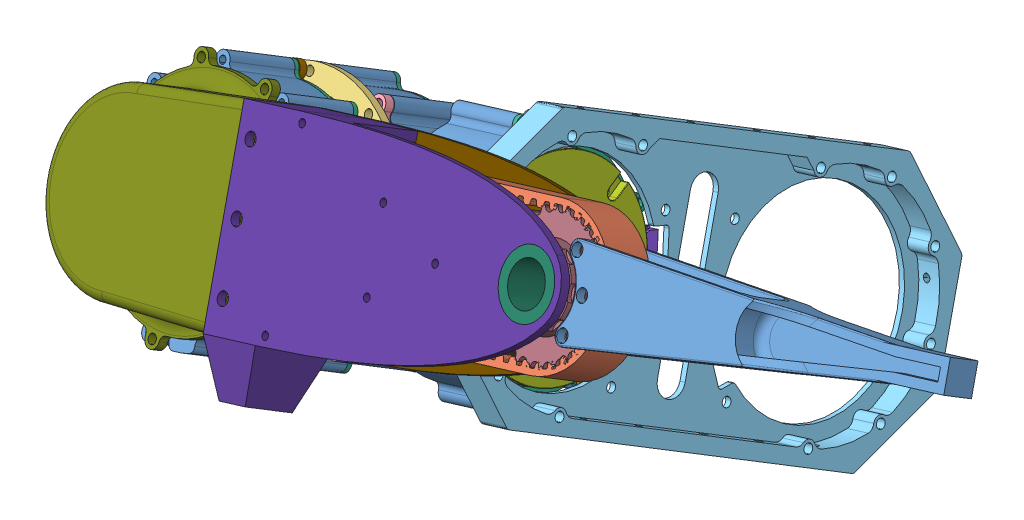
SolidWorks assembly 测试机械腿装配体, configuration 默认. Lengths in mm.
Overall size (357.51 213.54 232.86).
75 component instances, 23 part files, 47 mates.
Components (placement in the parent):
- CyberGearmotor.stp-1: CyberGearmotor.stp [默认] at (-16.9975 318.524 149.0781) x (0.513377 -0.714646 0.475105) z (0.144334 -0.473839 -0.868703) size (96.28 96.17 36.5)
  - ASM0002_ASM_1_ASM.stp-1: ASM0002_ASM_1_ASM.stp [默认] at origin size (96.28 96.17 36.5)
    - ASM0002_ASM_1_ASM_1_ASM.stp-1: ASM0002_ASM_1_ASM_1_ASM.stp [默认] at origin size (96.28 96.17 36.5)
      - 0714_ASM_1_ASM_1_ASM_1_ASM.stp-1: 0714_ASM_1_ASM_1_ASM_1_ASM.stp [默认] at origin size (96.28 96.17 36.5)
        - 3_1_02_067_0003_ASM_ASM_1_ASM_1_ASM.stp-1: 3_1_02_067_0003_ASM_ASM_1_ASM_1_ASM.stp [默认] at origin size (96.28 96.17 36.5)
          - 3_1_02_067_0003_ASM_1_ASM_1_ASM_ASM.stp-1: 3_1_02_067_0003_ASM_1_ASM_1_ASM_ASM.stp [默认] at origin size (96.28 96.17 36.5)
            - 1_1_06_EB673-504_1_1_1_1_1.stp-1: 1_1_06_EB673-504_1_1_1_1_1.stp [默认] at (39.8324 39.833 -22) size (79.19 78.95 25.5)
            - 1_2_04_670601_1_1_1_1_1.stp-1: 1_2_04_670601_1_1_1_1_1.stp [默认] at (93.9161 79.9966 -44) size (37 37 4)
            - 1_1_02_EB671-500_1_1_1_1_1.stp-1: 1_1_02_EB671-500_1_1_1_1_1.stp [默认] at (93.9161 79.9966 -44.4) x (-0.960973 0.276644 0) z (0 0 1) size (33 33 8.5)
            - 1_2_04_694000_1_1_1_1_1.stp-1: 1_2_04_694000_1_1_1_1_1.stp [默认] at (93.9161 79.9966 -44.5) size (11 11 4)
            - 1_2_06_000213_1_1_1_1_1.stp-1: 1_2_06_000213_1_1_1_1_1.stp [默认] at (93.9161 79.9966 -45.5) size (38.8 36.2 1.5)
            - 1_1_31_QT-642_1_1_1_1_1.stp-1: 1_1_31_QT-642_1_1_1_1_1.stp [默认] at (93.9161 79.9966 -22) x (-0.970555 -0.24088 0) z (0 0 -1) size (79.5 79.36 6)
            - 1_1_06_EB673-502_1_1_1_1_1.stp-1: 1_1_06_EB673-502_1_1_1_1_1.stp [默认] at (93.9161 79.9966 -13) x (-0.515958 -0.856614 0) z (0 0 -1) size (63 63 8)
          - 0518_ASM_2_ASM_1_ASM_1_ASM_1_AS_ASM.stp-1: 0518_ASM_2_ASM_1_ASM_1_ASM_1_AS_ASM.stp [默认] at (93.9161 79.9966 -17.235) x (0.235897 -0.971778 0) z (0 0 1) size (15.5 11.3 5.2)
            - 12345_ASM_1_ASM_2_ASM_1_ASM_1_A_ASM.stp-1: 12345_ASM_1_ASM_2_ASM_1_ASM_1_A_ASM.stp [默认] at origin size (15.5 11.3 5.2)
              - DUANZI_1_3_1_1_1_1_1_1.stp-1: DUANZI_1_3_1_1_1_1_1_1.stp [默认] at (-0.1798 16.5474 0.4329) x (0 0 -1) z (0 1 0) size (5.2 15.5 11.3)
      - LUODING_1_1.stp-1: LUODING_1_1.stp [默认] at (119.9375 52.9941 -20.5) x (-1 0 0) z (0 1 0) size (5.68 3 5.68)
      - LUODING_1_1.stp-2: LUODING_1_1.stp [默认] at (104.2902 116.0331 -20.5) x (-1 0 0) z (0 1 0) size (5.68 3 5.68)
      - LUODING_1_1.stp-3: LUODING_1_1.stp [默认] at (57.5205 70.9626 -20.5) x (-1 0 0) z (0 1 0) size (5.68 3 5.68)
  - 0411-2_4_1_3_1.stp-1: 0411-2_4_1_3_1.stp [默认] at (93.9161 79.9964 -17.5) x (0.235904 -0.971776 0) z (0 0 1) size (58 56.68 1.62)
- 带轮-1: 带轮 [默认] at (-46.1979 242.2295 263.5439) x (-0.758521 0.510794 -0.404643) z (0.144334 -0.473839 -0.868703) size (43.22 43.22 15)
- 带轮挡边-1: 带轮挡边 [默认] at (-44.0329 235.1219 250.5133) x (-0.758521 0.510794 -0.404643) z (0.144334 -0.473839 -0.868703) size (50 50 4)
- 带轮挡边-2: 带轮挡边 [默认] at (-46.7752 244.1248 267.0187) x (-0.171067 -0.876625 0.449738) z (0.144334 -0.473839 -0.868703) size (50 50 4)
- 膝关节带轮-1: 膝关节带轮 [默认] at (97.8102 306.0925 252.6362) x (-0.253129 0.831006 -0.495334) z (0.144334 -0.473839 -0.868703) size (43.22 43.22 23)
- 轴承-1: 轴承 [默认] at (105.7027 278.9198 247.4729) x (-0.639215 -0.714793 0.283683) z (-0.144334 0.473839 0.868703) size (23 23 4)
- 轴承-2: 轴承 [默认] at (102.9604 287.9227 263.9782) x (0.978394 -0.062991 0.196918) z (-0.144334 0.473839 0.868703) size (23 23 4)
- 膝关节转轴-1: 膝关节转轴 [默认] at (106.0635 277.7352 245.3011) x (-0.660093 -0.700126 0.272215) z (-0.144334 0.473839 0.868703) size (21 21 29)
- 大腿根部SLDPRT-3: 大腿根部SLDPRT [默认] at (-116.5184 238.2995 228.6787) x (-0.867463 -0.482981 0.119317) z (-0.144334 0.473839 0.868703) size (94.61 80.14 30.19)
- 大腿前部-1: 大腿前部 [默认] at (28.4879 261.8799 274.4435) x (0.253129 -0.831006 0.495334) z (0.956605 0.291387 0) size (78.5 27.01 129)
- 大腿前部盖子-1: 大腿前部盖子 [默认] at (28.7808 260.9183 240.4824) x (-0.253129 0.831006 -0.495334) z (0.956605 0.291387 0) size (72.83 15.76 129)
- 小腿2-1: 小腿2 [默认] at (167.4944 300.8487 252.6851) x (0.956605 0.291387 0) z (0.253129 -0.831006 0.495334) size (141.69 21.45 28.63)
- 5m同步带1-1: 5m同步带1 [默认] at (103.168 283.8435 257.0286) x (-0.144334 0.473839 0.868703) z (0.956605 0.291387 0) size (15 46.9 201.91)
- 连接盘-1: 连接盘 [默认] at (-38.0537 214.0176 210.6413) x (-0.962688 -0.270324 -0.0125) z (-0.228908 0.838094 -0.495176) size (80.5 7 80.5)
- CyberGearmotor.stp-2: CyberGearmotor.stp [默认] at (50.6838 277.1601 135.113) x (-0.021389 -0.879184 0.476002) z (0.144334 -0.473839 -0.868703) size (96.28 96.17 36.5)
  - ASM0002_ASM_1_ASM.stp-1: ASM0002_ASM_1_ASM.stp [默认] at origin size (96.28 96.17 36.5)
    - ASM0002_ASM_1_ASM_1_ASM.stp-1: ASM0002_ASM_1_ASM_1_ASM.stp [默认] at origin size (96.28 96.17 36.5)
      - 0714_ASM_1_ASM_1_ASM_1_ASM.stp-1: 0714_ASM_1_ASM_1_ASM_1_ASM.stp [默认] at origin size (96.28 96.17 36.5)
        - 3_1_02_067_0003_ASM_ASM_1_ASM_1_ASM.stp-1: 3_1_02_067_0003_ASM_ASM_1_ASM_1_ASM.stp [默认] at origin size (96.28 96.17 36.5)
          - 3_1_02_067_0003_ASM_1_ASM_1_ASM_ASM.stp-1: 3_1_02_067_0003_ASM_1_ASM_1_ASM_ASM.stp [默认] at origin size (96.28 96.17 36.5)
            - 1_1_06_EB673-504_1_1_1_1_1.stp-1: 1_1_06_EB673-504_1_1_1_1_1.stp [默认] at (39.8324 39.833 -22) size (79.19 78.95 25.5)
            - 1_2_04_670601_1_1_1_1_1.stp-1: 1_2_04_670601_1_1_1_1_1.stp [默认] at (93.9161 79.9966 -44) size (37 37 4)
            - 1_1_02_EB671-500_1_1_1_1_1.stp-1: 1_1_02_EB671-500_1_1_1_1_1.stp [默认] at (93.9161 79.9966 -44.4) x (-0.960973 0.276644 0) z (0 0 1) size (33 33 8.5)
            - 1_2_04_694000_1_1_1_1_1.stp-1: 1_2_04_694000_1_1_1_1_1.stp [默认] at (93.9161 79.9966 -44.5) size (11 11 4)
            - 1_2_06_000213_1_1_1_1_1.stp-1: 1_2_06_000213_1_1_1_1_1.stp [默认] at (93.9161 79.9966 -45.5) size (38.8 36.2 1.5)
            - 1_1_31_QT-642_1_1_1_1_1.stp-1: 1_1_31_QT-642_1_1_1_1_1.stp [默认] at (93.9161 79.9966 -22) x (-0.970555 -0.24088 0) z (0 0 -1) size (79.5 79.36 6)
            - 1_1_06_EB673-502_1_1_1_1_1.stp-1: 1_1_06_EB673-502_1_1_1_1_1.stp [默认] at (93.9161 79.9966 -13) x (-0.515958 -0.856614 0) z (0 0 -1) size (63 63 8)
          - 0518_ASM_2_ASM_1_ASM_1_ASM_1_AS_ASM.stp-1: 0518_ASM_2_ASM_1_ASM_1_ASM_1_AS_ASM.stp [默认] at (93.9161 79.9966 -17.235) x (0.235897 -0.971778 0) z (0 0 1) size (15.5 11.3 5.2)
            - 12345_ASM_1_ASM_2_ASM_1_ASM_1_A_ASM.stp-1: 12345_ASM_1_ASM_2_ASM_1_ASM_1_A_ASM.stp [默认] at origin size (15.5 11.3 5.2)
              - DUANZI_1_3_1_1_1_1_1_1.stp-1: DUANZI_1_3_1_1_1_1_1_1.stp [默认] at (-0.1798 16.5474 0.4329) x (0 0 -1) z (0 1 0) size (5.2 15.5 11.3)
      - LUODING_1_1.stp-1: LUODING_1_1.stp [默认] at (119.9375 52.9941 -20.5) x (-1 0 0) z (0 1 0) size (5.68 3 5.68)
      - LUODING_1_1.stp-2: LUODING_1_1.stp [默认] at (104.2902 116.0331 -20.5) x (-1 0 0) z (0 1 0) size (5.68 3 5.68)
      - LUODING_1_1.stp-3: LUODING_1_1.stp [默认] at (57.5205 70.9626 -20.5) x (-1 0 0) z (0 1 0) size (5.68 3 5.68)
  - 0411-2_4_1_3_1.stp-1: 0411-2_4_1_3_1.stp [默认] at (93.9161 79.9964 -17.5) x (0.235904 -0.971776 0) z (0 0 1) size (58 56.68 1.62)
- 肩关节连接器-1: 肩关节连接器 [默认] at (-5.8984 160.7238 245.2835) x (-0.021415 -0.879185 0.475999) z (0.989297 0.050099 0.137044) size (67.92 38.09 40.7)
- CyberGearmotor.stp-3: CyberGearmotor.stp [默认] at (56.3683 218.9179 320.1116) x (0.161386 -0.529819 -0.832614) z (0.956605 0.291387 0) size (96.28 96.17 36.5)
  - ASM0002_ASM_1_ASM.stp-1: ASM0002_ASM_1_ASM.stp [默认] at origin size (96.28 96.17 36.5)
    - ASM0002_ASM_1_ASM_1_ASM.stp-1: ASM0002_ASM_1_ASM_1_ASM.stp [默认] at origin size (96.28 96.17 36.5)
      - 0714_ASM_1_ASM_1_ASM_1_ASM.stp-1: 0714_ASM_1_ASM_1_ASM_1_ASM.stp [默认] at origin size (96.28 96.17 36.5)
        - 3_1_02_067_0003_ASM_ASM_1_ASM_1_ASM.stp-1: 3_1_02_067_0003_ASM_ASM_1_ASM_1_ASM.stp [默认] at origin size (96.28 96.17 36.5)
          - 3_1_02_067_0003_ASM_1_ASM_1_ASM_ASM.stp-1: 3_1_02_067_0003_ASM_1_ASM_1_ASM_ASM.stp [默认] at origin size (96.28 96.17 36.5)
            - 1_1_06_EB673-504_1_1_1_1_1.stp-1: 1_1_06_EB673-504_1_1_1_1_1.stp [默认] at (39.8324 39.833 -22) size (79.19 78.95 25.5)
            - 1_2_04_670601_1_1_1_1_1.stp-1: 1_2_04_670601_1_1_1_1_1.stp [默认] at (93.9161 79.9966 -44) size (37 37 4)
            - 1_1_02_EB671-500_1_1_1_1_1.stp-1: 1_1_02_EB671-500_1_1_1_1_1.stp [默认] at (93.9161 79.9966 -44.4) x (-0.960973 0.276644 0) z (0 0 1) size (33 33 8.5)
            - 1_2_04_694000_1_1_1_1_1.stp-1: 1_2_04_694000_1_1_1_1_1.stp [默认] at (93.9161 79.9966 -44.5) size (11 11 4)
            - 1_2_06_000213_1_1_1_1_1.stp-1: 1_2_06_000213_1_1_1_1_1.stp [默认] at (93.9161 79.9966 -45.5) size (38.8 36.2 1.5)
            - 1_1_31_QT-642_1_1_1_1_1.stp-1: 1_1_31_QT-642_1_1_1_1_1.stp [默认] at (93.9161 79.9966 -22) x (-0.970555 -0.24088 0) z (0 0 -1) size (79.5 79.36 6)
            - 1_1_06_EB673-502_1_1_1_1_1.stp-1: 1_1_06_EB673-502_1_1_1_1_1.stp [默认] at (93.9161 79.9966 -13) x (-0.515958 -0.856614 0) z (0 0 -1) size (63 63 8)
          - 0518_ASM_2_ASM_1_ASM_1_ASM_1_AS_ASM.stp-1: 0518_ASM_2_ASM_1_ASM_1_ASM_1_AS_ASM.stp [默认] at (93.9161 79.9966 -17.235) x (0.235897 -0.971778 0) z (0 0 1) size (15.5 11.3 5.2)
            - 12345_ASM_1_ASM_2_ASM_1_ASM_1_A_ASM.stp-1: 12345_ASM_1_ASM_2_ASM_1_ASM_1_A_ASM.stp [默认] at origin size (15.5 11.3 5.2)
              - DUANZI_1_3_1_1_1_1_1_1.stp-1: DUANZI_1_3_1_1_1_1_1_1.stp [默认] at (-0.1798 16.5474 0.4329) x (0 0 -1) z (0 1 0) size (5.2 15.5 11.3)
      - LUODING_1_1.stp-1: LUODING_1_1.stp [默认] at (119.9375 52.9941 -20.5) x (-1 0 0) z (0 1 0) size (5.68 3 5.68)
      - LUODING_1_1.stp-2: LUODING_1_1.stp [默认] at (104.2902 116.0331 -20.5) x (-1 0 0) z (0 1 0) size (5.68 3 5.68)
      - LUODING_1_1.stp-3: LUODING_1_1.stp [默认] at (57.5205 70.9626 -20.5) x (-1 0 0) z (0 1 0) size (5.68 3 5.68)
  - 0411-2_4_1_3_1.stp-1: 0411-2_4_1_3_1.stp [默认] at (93.9161 79.9964 -17.5) x (0.235904 -0.971776 0) z (0 0 1) size (58 56.68 1.62)
- 肩膀-1: 肩膀 [默认] at (40.6375 229.3786 197.6094) x (0.144334 -0.473839 -0.868703) z (0.253129 -0.831006 0.495334) size (175 10 85)
Mates (geometry in assembly coordinates):
- 同心1: concentric aligned: cylinder of CyberGearmotor.stp-1/ASM0002_ASM_1_ASM.stp-1/ASM0002_ASM_1_ASM_1_ASM.stp-1/0714_ASM_1_ASM_1_ASM_1_ASM.stp-1/3_1_02_067_0003_ASM_ASM_1_ASM_1_ASM.stp-1/3_1_02_067_0003_ASM_1_ASM_1_ASM_ASM.stp-1/1_1_02_EB671-500_1_1_1_1_1.stp-1 through (-42.8638 231.2838 243.4769) axis (-0.144334 0.473839 0.868703) radius 16.5; cylinder of 带轮挡边-1 through (-43.4556 233.2265 247.0385) axis (-0.144334 0.473839 0.868703) radius 25
- 重合1: coincident anti-aligned: plane of CyberGearmotor.stp-1/ASM0002_ASM_1_ASM.stp-1/ASM0002_ASM_1_ASM_1_ASM.stp-1/0714_ASM_1_ASM_1_ASM_1_ASM.stp-1/3_1_02_067_0003_ASM_ASM_1_ASM_1_ASM.stp-1/3_1_02_067_0003_ASM_1_ASM_1_ASM_ASM.stp-1/1_1_02_EB671-500_1_1_1_1_1.stp-1 through (-43.4556 233.2265 247.0385) normal (-0.144334 0.473839 0.868703); plane of 带轮挡边-1 through (-43.4556 233.2265 247.0385) normal (0.144334 -0.473839 -0.868703)
- 重合4: coincident anti-aligned: plane of 带轮-1 through (-32.6774 251.5874 243.4188) normal (0.144334 -0.473839 -0.868703); plane of 带轮挡边-1 through (-44.0329 235.1219 250.5133) normal (-0.144334 0.473839 0.868703)
- 同心12: concentric aligned: cylinder of CyberGearmotor.stp-1/ASM0002_ASM_1_ASM.stp-1/ASM0002_ASM_1_ASM_1_ASM.stp-1/0714_ASM_1_ASM_1_ASM_1_ASM.stp-1/3_1_02_067_0003_ASM_ASM_1_ASM_1_ASM.stp-1/3_1_02_067_0003_ASM_1_ASM_1_ASM_ASM.stp-1/1_1_02_EB671-500_1_1_1_1_1.stp-1 through (-42.8638 231.2838 243.4769) axis (-0.144334 0.473839 0.868703) radius 16.5; cylinder of 带轮挡边-2 through (-46.1979 242.2295 263.5439) axis (-0.144334 0.473839 0.868703) radius 25
- 重合5: coincident anti-aligned: plane of 带轮-1 through (-34.8425 258.695 256.4493) normal (-0.144334 0.473839 0.868703); plane of 带轮挡边-2 through (-46.1979 242.2295 263.5439) normal (0.144334 -0.473839 -0.868703)
- 同心20: concentric aligned: cylinder of 轴承-1 through (105.1254 280.8151 250.9477) axis (0.144334 -0.473839 -0.868703) radius 8.5; cylinder of 膝关节转轴-1 through (102.0222 291.0027 269.6248) axis (0.144334 -0.473839 -0.868703) radius 8.5
- 重合12: coincident anti-aligned: plane of CyberGearmotor.stp-1/ASM0002_ASM_1_ASM.stp-1/ASM0002_ASM_1_ASM_1_ASM.stp-1/0714_ASM_1_ASM_1_ASM_1_ASM.stp-1/3_1_02_067_0003_ASM_ASM_1_ASM_1_ASM.stp-1/3_1_02_067_0003_ASM_1_ASM_1_ASM_ASM.stp-1/1_1_06_EB673-504_1_1_1_1_1.stp-1 through (-42.2096 231.838 244.5495) normal (-0.144334 0.473839 0.868703); plane of 大腿根部SLDPRT-3 through (-116.5184 238.2995 228.6787) normal (0.144334 -0.473839 -0.868703)
- 重合17: coincident anti-aligned: plane of 大腿根部SLDPRT-3 through (-7.1399 285.5975 252.1337) normal (-0.144334 0.473839 0.868703); plane of 大腿前部-1 through (28.9209 260.4584 271.8374) normal (0.144334 -0.473839 -0.868703)
- 重合18: coincident anti-aligned: plane of 大腿根部SLDPRT-3 through (-12.8089 269.8899 228.6787) normal (0.956605 0.291387 0); plane of 大腿前部-1 through (-6.6368 249.6273 271.8374) normal (-0.956605 -0.291387 0)
- 重合21: coincident anti-aligned: plane of 大腿根部SLDPRT-3 through (11.8953 223.1062 258.3018) normal (0.253129 -0.831006 0.495334); plane of 大腿前部-1 through (37.454 232.4449 260.9079) normal (-0.253129 0.831006 -0.495334)
- 同心32: concentric anti-aligned: cylinder of 膝关节转轴-1 through (102.0222 291.0027 269.6248) axis (0.144334 -0.473839 -0.868703) radius 8.5; cylinder of 大腿前部-1 through (102.3109 290.055 267.8874) axis (-0.144334 0.473839 0.868703) radius 8.5
- 重合23: coincident aligned: plane of 膝关节转轴-1 through (101.8779 291.4765 270.4935) normal (-0.144334 0.473839 0.868703); plane of 大腿前部-1 through (28.4879 261.8799 274.4435) normal (-0.144334 0.473839 0.868703)
- 重合32: coincident anti-aligned: plane of 带轮挡边-1 through (-44.0329 235.1219 250.5133) normal (-0.144334 0.473839 0.868703); plane of 5m同步带1-1 through (99.277 296.6173 240.781) normal (0.144334 -0.473839 -0.868703)
- 同心44: concentric aligned: cylinder of 带轮挡边-1 through (-43.4556 233.2265 247.0385) axis (-0.144334 0.473839 0.868703) radius 25; cylinder of 5m同步带1-1 through (-45.1154 238.6757 257.0286) axis (-0.144334 0.473839 0.868703) radius 23.448
- 同心47: concentric anti-aligned: cylinder of 膝关节带轮-1 through (105.1975 280.5782 250.5133) axis (-0.144334 0.473839 0.868703) radius 10.5; cylinder of 膝关节转轴-1 through (102.0222 291.0027 269.6248) axis (0.144334 -0.473839 -0.868703) radius 8.5
- 重合38: coincident anti-aligned: plane of 带轮-1 through (-32.6774 251.5874 243.4188) normal (0.144334 -0.473839 -0.868703); plane of 带轮挡边-1 through (-44.0329 235.1219 250.5133) normal (-0.144334 0.473839 0.868703)
- 重合39: coincident aligned: plane of 带轮-1 through (-34.8425 258.695 256.4493) normal (-0.144334 0.473839 0.868703); plane of 膝关节带轮-1 through (122.457 296.0468 262.2107) normal (-0.144334 0.473839 0.868703)
- 重合41: coincident anti-aligned: plane of 膝关节带轮-1 through (105.1819 280.829 250.9495) normal (0.144334 -0.473839 -0.868703); plane of 轴承-1 through (105.1254 280.8151 250.9477) normal (-0.144334 0.473839 0.868703)
- 重合42: coincident anti-aligned: plane of 膝关节带轮-1 through (122.457 296.0468 262.2107) normal (-0.144334 0.473839 0.868703); plane of 小腿2-1 through (165.6902 306.7716 263.5439) normal (0.144334 -0.473839 -0.868703)
- 同心50: concentric aligned: cylinder of 膝关节带轮-1 through (118.8841 274.4731 256.1174) axis (0.144334 -0.473839 -0.868703) radius 1.65; cylinder of 小腿2-1 through (112.1004 296.7436 296.9464) axis (0.144334 -0.473839 -0.868703) radius 2.1
- 同心51: concentric aligned: cylinder of 膝关节带轮-1 through (120.5032 285.2404 250.5133) axis (0.144334 -0.473839 -0.868703) radius 1.65; cylinder of 小腿2-1 through (113.7195 307.5108 291.3424) axis (0.144334 -0.473839 -0.868703) radius 2.1
- 同心53: concentric aligned: circle of 轴承-2; cylinder of 膝关节转轴-1 through (105.3419 280.1044 249.6446) axis (-0.144334 0.473839 0.868703) radius 7
- 重合44: coincident anti-aligned: plane of 大腿根部SLDPRT-3 through (-3.6758 274.2253 231.2848) normal (0.144334 -0.473839 -0.868703); plane of 大腿前部盖子-1 through (28.3478 262.3398 243.0885) normal (-0.144334 0.473839 0.868703)
- 同心54: concentric anti-aligned: cylinder of 大腿根部SLDPRT-3 through (-9.188 275.1622 257.4854) axis (-0.144334 0.473839 0.868703) radius 1.65; cylinder of 大腿前部盖子-1 through (-5.724 263.79 236.6365) axis (0.144334 -0.473839 -0.868703) radius 2.1
- 同心55: concentric anti-aligned: cylinder of 大腿根部SLDPRT-3 through (1.4434 240.2599 278.2894) axis (-0.144334 0.473839 0.868703) radius 1.65; cylinder of 大腿前部盖子-1 through (4.9074 228.8878 257.4405) axis (0.144334 -0.473839 -0.868703) radius 2.1
- 重合45: coincident anti-aligned: plane of CyberGearmotor.stp-1/ASM0002_ASM_1_ASM.stp-1/ASM0002_ASM_1_ASM_1_ASM.stp-1/0714_ASM_1_ASM_1_ASM_1_ASM.stp-1/3_1_02_067_0003_ASM_ASM_1_ASM_1_ASM.stp-1/3_1_02_067_0003_ASM_1_ASM_1_ASM_ASM.stp-1/1_1_06_EB673-502_1_1_1_1_1.stp-1 through (-38.1874 215.9314 215.3309) normal (0.144334 -0.473839 -0.868703); plane of 连接盘-1 through (-38.7753 216.3868 214.9848) normal (-0.144334 0.473839 0.868703)
- 同心56: concentric aligned: cylinder of CyberGearmotor.stp-1/ASM0002_ASM_1_ASM.stp-1/ASM0002_ASM_1_ASM_1_ASM.stp-1/0714_ASM_1_ASM_1_ASM_1_ASM.stp-1/3_1_02_067_0003_ASM_ASM_1_ASM_1_ASM.stp-1/3_1_02_067_0003_ASM_1_ASM_1_ASM_ASM.stp-1/1_1_06_EB673-502_1_1_1_1_1.stp-1 through (-39.342 219.7221 222.2805) axis (0.144334 -0.473839 -0.868703) radius 31.5; cylinder of 连接盘-1 through (-38.1874 215.9314 215.3309) axis (0.144334 -0.473839 -0.868703) radius 40.25
- 同心57: concentric aligned: cylinder of CyberGearmotor.stp-1/ASM0002_ASM_1_ASM.stp-1/ASM0002_ASM_1_ASM_1_ASM.stp-1/0714_ASM_1_ASM_1_ASM_1_ASM.stp-1/3_1_02_067_0003_ASM_ASM_1_ASM_1_ASM.stp-1/3_1_02_067_0003_ASM_1_ASM_1_ASM_ASM.stp-1/1_1_31_QT-642_1_1_1_1_1.stp-1 through (-25.1026 251.3327 207.9798) axis (0.144334 -0.473839 -0.868703) radius 1.55; cylinder of 连接盘-1 through (-23.8757 247.305 200.5958) axis (0.144334 -0.473839 -0.868703) radius 1.55
- 同心61: concentric aligned: cylinder of CyberGearmotor.stp-1/ASM0002_ASM_1_ASM.stp-1/ASM0002_ASM_1_ASM_1_ASM.stp-1/0714_ASM_1_ASM_1_ASM_1_ASM.stp-1/3_1_02_067_0003_ASM_ASM_1_ASM_1_ASM.stp-1/3_1_02_067_0003_ASM_1_ASM_1_ASM_ASM.stp-1/1_1_06_EB673-502_1_1_1_1_1.stp-1 through (-39.342 219.7221 222.2805) axis (0.144334 -0.473839 -0.868703) radius 31.5; cylinder of CyberGearmotor.stp-2/ASM0002_ASM_1_ASM.stp-1/ASM0002_ASM_1_ASM_1_ASM.stp-1/0714_ASM_1_ASM_1_ASM_1_ASM.stp-1/3_1_02_067_0003_ASM_ASM_1_ASM_1_ASM.stp-1/3_1_02_067_0003_ASM_1_ASM_1_ASM_ASM.stp-1/1_1_06_EB673-502_1_1_1_1_1.stp-1 through (-33.3522 200.0578 186.2293) axis (0.144334 -0.473839 -0.868703) radius 31.5
- 重合48: coincident anti-aligned: plane of 连接盘-1 through (-38.0537 214.0176 210.6413) normal (0.144334 -0.473839 -0.868703); plane of CyberGearmotor.stp-2/ASM0002_ASM_1_ASM.stp-1/ASM0002_ASM_1_ASM_1_ASM.stp-1/0714_ASM_1_ASM_1_ASM_1_ASM.stp-1/3_1_02_067_0003_ASM_ASM_1_ASM_1_ASM.stp-1/3_1_02_067_0003_ASM_1_ASM_1_ASM_ASM.stp-1/1_1_02_EB671-500_1_1_1_1_1.stp-1 through (-37.4657 213.5622 210.9874) normal (-0.144334 0.473839 0.868703)
- 平行4: parallel aligned: plane of 大腿前部-1 through (34.7494 241.324 283.2427) normal (0.253129 -0.831006 0.495334); plane of 5m同步带1-1 through (-38.0975 215.6365 262.1279) normal (0.253129 -0.831006 0.495334)
- 同心70: concentric anti-aligned: cylinder of CyberGearmotor.stp-2/ASM0002_ASM_1_ASM.stp-1/ASM0002_ASM_1_ASM_1_ASM.stp-1/0714_ASM_1_ASM_1_ASM_1_ASM.stp-1/3_1_02_067_0003_ASM_ASM_1_ASM_1_ASM.stp-1/3_1_02_067_0003_ASM_1_ASM_1_ASM_ASM.stp-1/1_1_31_QT-642_1_1_1_1_1.stp-1 through (-33.4244 200.2947 186.6637) axis (0.144334 -0.473839 -0.868703) radius 32; cylinder of 肩关节连接器-1 through (-32.9914 198.8732 184.0576) axis (-0.144334 0.473839 0.868703) radius 32
- 重合51: coincident anti-aligned: plane of CyberGearmotor.stp-2/ASM0002_ASM_1_ASM.stp-1/ASM0002_ASM_1_ASM_1_ASM.stp-1/0714_ASM_1_ASM_1_ASM_1_ASM.stp-1/3_1_02_067_0003_ASM_ASM_1_ASM_1_ASM.stp-1/3_1_02_067_0003_ASM_1_ASM_1_ASM_ASM.stp-1/1_1_31_QT-642_1_1_1_1_1.stp-1 through (-33.4244 200.2947 186.6637) normal (0.144334 -0.473839 -0.868703); plane of 肩关节连接器-1 through (-1.8282 147.3615 220.7861) normal (-0.144334 0.473839 0.868703)
- 同心71: concentric aligned: cylinder of CyberGearmotor.stp-2/ASM0002_ASM_1_ASM.stp-1/ASM0002_ASM_1_ASM_1_ASM.stp-1/0714_ASM_1_ASM_1_ASM_1_ASM.stp-1/3_1_02_067_0003_ASM_ASM_1_ASM_1_ASM.stp-1/3_1_02_067_0003_ASM_1_ASM_1_ASM_ASM.stp-1/1_1_06_EB673-504_1_1_1_1_1.stp-1 through (-3.1103 221.7091 181.2054) axis (-0.144334 0.473839 0.868703) radius 1.25; cylinder of 肩关节连接器-1 through (0.6179 209.4698 158.7668) axis (-0.144334 0.473839 0.868703) radius 1.55
- 重合52: coincident anti-aligned: plane of 肩关节连接器-1 through (20.9072 168.8889 245.2835) normal (0.956605 0.291387 0); plane of CyberGearmotor.stp-3/ASM0002_ASM_1_ASM.stp-1/ASM0002_ASM_1_ASM_1_ASM.stp-1/0714_ASM_1_ASM_1_ASM_1_ASM.stp-1/3_1_02_067_0003_ASM_ASM_1_ASM_1_ASM.stp-1/3_1_02_067_0003_ASM_1_ASM_1_ASM_ASM.stp-1/1_1_02_EB671-500_1_1_1_1_1.stp-1 through (5.7214 218.743 197.6094) normal (-0.956605 -0.291387 0)
- 同心72: concentric anti-aligned: cylinder of 肩关节连接器-1 through (-37.8855 205.4601 197.6094) axis (0.956605 0.291387 0) radius 21; cylinder of CyberGearmotor.stp-3/ASM0002_ASM_1_ASM.stp-1/ASM0002_ASM_1_ASM_1_ASM.stp-1/0714_ASM_1_ASM_1_ASM_1_ASM.stp-1/3_1_02_067_0003_ASM_ASM_1_ASM_1_ASM.stp-1/3_1_02_067_0003_ASM_1_ASM_1_ASM_ASM.stp-1/1_1_02_EB671-500_1_1_1_1_1.stp-1 through (9.6435 219.9377 197.6094) axis (-0.956605 -0.291387 0) radius 16.5
- 同心87: concentric aligned: cylinder of CyberGearmotor.stp-1/ASM0002_ASM_1_ASM.stp-1/ASM0002_ASM_1_ASM_1_ASM.stp-1/0714_ASM_1_ASM_1_ASM_1_ASM.stp-1/3_1_02_067_0003_ASM_ASM_1_ASM_1_ASM.stp-1/3_1_02_067_0003_ASM_1_ASM_1_ASM_ASM.stp-1/1_1_06_EB673-504_1_1_1_1_1.stp-1 through (-43.3342 232.828 246.3079) axis (0.144334 -0.473839 -0.868703) radius 21.5; cylinder of 大腿根部SLDPRT-3 through (-47.3526 246.0202 270.4935) axis (0.144334 -0.473839 -0.868703) radius 29
- 同心90: concentric aligned: cylinder of 带轮-1 through (-42.1279 232.6171 269.4632) axis (-0.144334 0.473839 0.868703) radius 2.05; cylinder of 带轮挡边-2 through (-41.2619 229.7741 264.251) axis (-0.144334 0.473839 0.868703) radius 2.05
- 同心91: concentric aligned: cylinder of 带轮-1 through (-42.1279 232.6171 269.4632) axis (-0.144334 0.473839 0.868703) radius 2.05; cylinder of 带轮挡边-1 through (-38.5196 220.7712 247.7456) axis (-0.144334 0.473839 0.868703) radius 2.05
- 重合55: coincident anti-aligned: plane of 膝关节带轮-1 through (103.0169 287.9366 263.98) normal (-0.144334 0.473839 0.868703); plane of 轴承-2 through (102.9604 287.9227 263.9782) normal (0.144334 -0.473839 -0.868703)
- 重合56: coincident anti-aligned: plane of CyberGearmotor.stp-3/ASM0002_ASM_1_ASM.stp-1/ASM0002_ASM_1_ASM_1_ASM.stp-1/0714_ASM_1_ASM_1_ASM_1_ASM.stp-1/3_1_02_067_0003_ASM_ASM_1_ASM_1_ASM.stp-1/3_1_02_067_0003_ASM_1_ASM_1_ASM_ASM.stp-1/1_1_06_EB673-502_1_1_1_1_1.stp-1 through (40.6375 229.3786 197.6094) normal (0.956605 0.291387 0); plane of 肩膀-1 through (40.6375 229.3786 197.6094) normal (-0.956605 -0.291387 0)
- 同心92: concentric anti-aligned: cylinder of CyberGearmotor.stp-3/ASM0002_ASM_1_ASM.stp-1/ASM0002_ASM_1_ASM_1_ASM.stp-1/0714_ASM_1_ASM_1_ASM_1_ASM.stp-1/3_1_02_067_0003_ASM_ASM_1_ASM_1_ASM.stp-1/3_1_02_067_0003_ASM_1_ASM_1_ASM_ASM.stp-1/1_1_06_EB673-502_1_1_1_1_1.stp-1 through (32.9846 227.0475 197.6094) axis (0.956605 0.291387 0) radius 31.5; cylinder of 肩膀-1 through (42.5507 229.9614 197.6094) axis (-0.956605 -0.291387 0) radius 32.5
- 同心93: concentric aligned: cylinder of CyberGearmotor.stp-3/ASM0002_ASM_1_ASM.stp-1/ASM0002_ASM_1_ASM_1_ASM.stp-1/0714_ASM_1_ASM_1_ASM_1_ASM.stp-1/3_1_02_067_0003_ASM_ASM_1_ASM_1_ASM.stp-1/3_1_02_067_0003_ASM_1_ASM_1_ASM_ASM.stp-1/1_1_06_EB673-504_1_1_1_1_1.stp-1 through (22.0875 257.5715 216.5338) axis (-0.956605 -0.291387 0) radius 1.25; cylinder of 肩膀-1 through (40.77 263.2622 216.5338) axis (-0.956605 -0.291387 0) radius 1.55
- 平行5: parallel anti-aligned: plane of 大腿前部盖子-1 through (28.7808 260.9183 240.4824) normal (0.144334 -0.473839 -0.868703); plane of 肩膀-1 through (44.0694 252.4307 234.5292) normal (-0.144334 0.473839 0.868703)
- 平行6: parallel aligned: plane of 小腿2-1 through (164.7854 309.7421 258.8955) normal (-0.253129 0.831006 -0.495334); plane of 肩膀-1 through (39.4456 267.6102 176.5577) normal (-0.253129 0.831006 -0.495334)
- 平行7: parallel aligned: plane of 5m同步带1-1 through (98.3151 299.7752 238.8987) normal (-0.253129 0.831006 -0.495334); plane of 肩膀-1 through (39.4456 267.6102 176.5577) normal (-0.253129 0.831006 -0.495334)
- 平行8: parallel aligned: plane of 大腿前部-1 through (34.7494 241.324 283.2427) normal (0.253129 -0.831006 0.495334); plane of 肩膀-1 through (60.9615 196.9748 218.661) normal (0.253129 -0.831006 0.495334)
